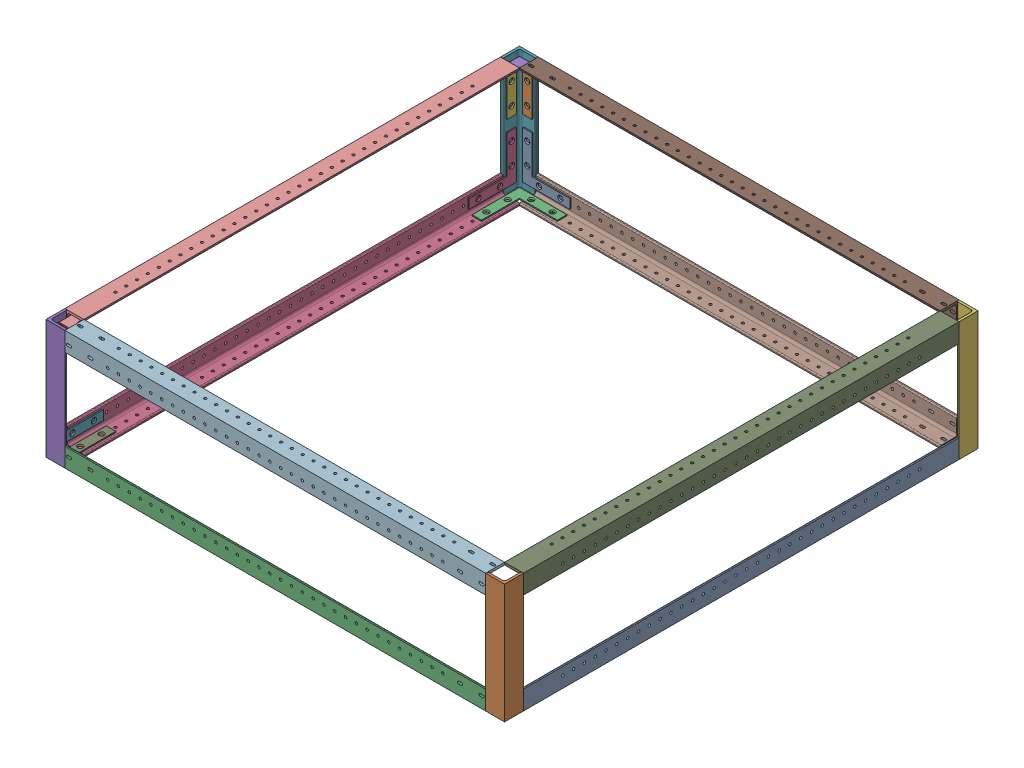
SolidWorks assembly Frame Assembly, configuration Default. Lengths in mm.
Overall size (614.8 160 634.8).
27 component instances, 4 part files, 110 mates.
Components (placement in the parent):
- 1 inch 584mm L Angle-1: 1 inch 584mm L Angle [8982K404] at (148.0756 139.9315 -175.8102) size (25.4 25.4 584)
- 1 inch 160mm L Angle-5: 1 inch 160mm L Angle [8982K404] at (148.0756 -322.3685 446.4898) x (1 0 0) z (0 1 0) size (25.4 25.4 160)
- 1 inch 564mm L Angle-3: 1 inch 564mm L Angle [8982K404] at (180.9756 139.9315 446.4898) x (0 0 1) z (-1 0 0) size (25.4 25.4 564)
- 1 inch 584mm L Angle-2: 1 inch 584mm L Angle [8982K404] at (-441.3244 139.9315 -175.8102) x (0 -1 0) z (0 0 1) size (25.4 25.4 584)
- 1 inch 160mm L Angle-2: 1 inch 160mm L Angle [8982K404] at (-441.3244 736.8315 446.4898) x (-1 0 0) z (0 -1 0) size (25.4 25.4 160)
- 1 inch 160mm L Angle-3: 1 inch 160mm L Angle [8982K404] at (148.0756 736.8315 -162.9102) x (1 0 0) z (0 -1 0) size (25.4 25.4 160)
- 1 inch 160mm L Angle-4: 1 inch 160mm L Angle [8982K404] at (-441.3244 736.8315 -162.9102) x (0 0 -1) z (0 -1 0) size (25.4 25.4 160)
- 1 inch 564mm L Angle-2: 1 inch 564mm L Angle [8982K404] at (-474.2244 139.9315 -162.9102) x (0 0 -1) z (1 0 0) size (25.4 25.4 564) (hidden)
- 1 inch 584mm L Angle-3: 1 inch 584mm L Angle [8982K404] at (148.0756 274.5315 -175.8102) x (0 1 0) z (0 0 1) size (25.4 25.4 584)
- 1 inch 584mm L Angle-4: 1 inch 584mm L Angle [8982K404] at (-441.3244 274.5315 -175.8102) x (-1 0 0) z (0 0 1) size (25.4 25.4 584)
- 1 inch 564mm L Angle-4: 1 inch 564mm L Angle [8982K404] at (-474.2244 274.5315 -162.9102) x (0 1 0) z (1 0 0) size (25.4 25.4 564) (hidden)
- 1 inch 564mm L Angle-5: 1 inch 564mm L Angle [8982K404] at (180.9756 274.5315 446.4898) x (0 1 0) z (-1 0 0) size (25.4 25.4 564) (hidden)
- 1558A14_L-Shape Flat-Surface Bracket with 2-1-2 Long Sides (2)-2: 1558A14_L-Shape Flat-Surface Bracket with 2-1-2 Long Sides (2) [1558A14] at (-413.5419 167.714 -171.6732) size (63.5 63.5 1.52)
- 1558A14_L-Shape Flat-Surface Bracket with 2-1-2 Long Sides (2)-3: 1558A14_L-Shape Flat-Surface Bracket with 2-1-2 Long Sides (2) [1558A14] at (-413.5419 246.749 -171.6732) x (0 -1 0) z (0 0 1) size (63.5 63.5 1.52)
- 1558A14_L-Shape Flat-Surface Bracket with 2-1-2 Long Sides (2)-4: 1558A14_L-Shape Flat-Surface Bracket with 2-1-2 Long Sides (2) [1558A14] at (-413.5419 131.1685 -135.1277) x (0 0 1) z (0 1 0) size (63.5 63.5 1.52)
- 1558A14_L-Shape Flat-Surface Bracket with 2-1-2 Long Sides (2)-6: 1558A14_L-Shape Flat-Surface Bracket with 2-1-2 Long Sides (2) [1558A14] at (-450.0874 167.714 -135.1302) x (0 1 0) z (1 0 0) size (63.5 63.5 1.52)
- 1558A14_L-Shape Flat-Surface Bracket with 2-1-2 Long Sides (2)-8: 1558A14_L-Shape Flat-Surface Bracket with 2-1-2 Long Sides (2) [1558A14] at (-413.5419 283.2945 -135.1277) x (1 0 0) z (0 -1 0) size (63.5 63.5 1.52)
- 1558A14_L-Shape Flat-Surface Bracket with 2-1-2 Long Sides (2)-27: 1558A14_L-Shape Flat-Surface Bracket with 2-1-2 Long Sides (2) [1558A14] at (-450.0874 246.7515 -135.1302) x (0 0 1) z (1 0 0) size (63.5 63.5 1.52)
- 1558A14_L-Shape Flat-Surface Bracket with 2-1-2 Long Sides (2)-36: 1558A14_L-Shape Flat-Surface Bracket with 2-1-2 Long Sides (2) [1558A14] at (-450.0874 167.714 418.7073) x (0 0 -1) z (1 0 0) size (63.5 63.5 1.52)
- 1558A14_L-Shape Flat-Surface Bracket with 2-1-2 Long Sides (2)-37: 1558A14_L-Shape Flat-Surface Bracket with 2-1-2 Long Sides (2) [1558A14] at (-413.5419 167.714 455.2528) x (0 1 0) z (0 0 -1) size (63.5 63.5 1.52)
- 1558A14_L-Shape Flat-Surface Bracket with 2-1-2 Long Sides (2)-38: 1558A14_L-Shape Flat-Surface Bracket with 2-1-2 Long Sides (2) [1558A14] at (-413.5419 131.1685 418.7073) x (1 0 0) z (0 1 0) size (63.5 63.5 1.52)
- 1558A14_L-Shape Flat-Surface Bracket with 2-1-2 Long Sides (2)-39: 1558A14_L-Shape Flat-Surface Bracket with 2-1-2 Long Sides (2) [1558A14] at (-413.5419 283.2945 418.7073) x (0 0 -1) z (0 -1 0) size (63.5 63.5 1.52)
- 1558A14_L-Shape Flat-Surface Bracket with 2-1-2 Long Sides (2)-40: 1558A14_L-Shape Flat-Surface Bracket with 2-1-2 Long Sides (2) [1558A14] at (-450.0874 246.749 418.7073) x (0 -1 0) z (1 0 0) size (63.5 63.5 1.52)
- 1558A14_L-Shape Flat-Surface Bracket with 2-1-2 Long Sides (2)-41: 1558A14_L-Shape Flat-Surface Bracket with 2-1-2 Long Sides (2) [1558A14] at (-413.5419 246.749 455.2528) x (1 0 0) z (0 0 -1) size (63.5 63.5 1.52)
- 1558A14_L-Shape Flat-Surface Bracket with 2-1-2 Long Sides (2)-42: 1558A14_L-Shape Flat-Surface Bracket with 2-1-2 Long Sides (2) [1558A14] at (120.2931 167.714 455.2528) x (-1 0 0) z (0 0 -1) size (63.5 63.5 1.52)
- 1558A14_L-Shape Flat-Surface Bracket with 2-1-2 Long Sides (2)-43: 1558A14_L-Shape Flat-Surface Bracket with 2-1-2 Long Sides (2) [1558A14] at (120.2931 131.1685 418.7073) x (0 0 -1) z (0 1 0) size (63.5 63.5 1.52)
- 1558A14_L-Shape Flat-Surface Bracket with 2-1-2 Long Sides (2)-44: 1558A14_L-Shape Flat-Surface Bracket with 2-1-2 Long Sides (2) [1558A14] at (156.8386 167.714 418.7073) x (0 1 0) z (-1 0 0) size (63.5 63.5 1.52)
Mates (geometry in assembly coordinates):
- Parallel1: parallel aligned: plane of 1 inch 584mm L Angle-1 through (159.1881 151.044 433.7898) normal (0 0 1); plane of 1 inch 160mm L Angle-5 through (135.3756 287.2315 459.1898) normal (0 0 1)
- Coincident3: coincident aligned: plane of 1 inch 584mm L Angle-1 through (160.7756 127.2315 433.7898) normal (1 0 0); plane of 1 inch 160mm L Angle-5 through (160.7756 287.2315 459.1898) normal (1 0 0)
- Coincident4: coincident anti-aligned: plane of 1 inch 584mm L Angle-1 through (159.1881 151.044 433.7898) normal (0 0 1); plane of 1 inch 160mm L Angle-5 through (159.1881 287.2315 433.7898) normal (0 0 -1)
- Parallel3: parallel aligned: plane of 1 inch 584mm L Angle-1 through (135.3756 127.2315 433.7898) normal (0 -1 0); plane of 1 inch 564mm L Angle-3 through (-428.6244 127.2315 433.7898) normal (0 -1 0)
- Coincident9: coincident aligned: plane of 1 inch 160mm L Angle-5 through (135.3756 287.2315 459.1898) normal (0 0 1); plane of 1 inch 564mm L Angle-3 through (-428.6244 127.2315 459.1898) normal (0 0 1)
- Parallel4: parallel anti-aligned: plane of 1 inch 564mm L Angle-3 through (-428.6244 130.4065 452.8398) normal (0 1 0); plane of 1 inch 584mm L Angle-2 through (-454.0244 127.2315 433.7898) normal (0 -1 0)
- Coincident12: coincident aligned: plane of 1 inch 564mm L Angle-3 through (-428.6244 127.2315 433.7898) normal (0 -1 0); plane of 1 inch 584mm L Angle-2 through (-454.0244 127.2315 433.7898) normal (0 -1 0)
- Coincident13: coincident anti-aligned: plane of 1 inch 564mm L Angle-3 through (-428.6244 151.044 457.6023) normal (-1 0 0); plane of 1 inch 584mm L Angle-2 through (-428.6244 128.819 433.7898) normal (1 0 0)
- Coincident15: coincident anti-aligned: plane of 1 inch 564mm L Angle-3 through (-428.6244 128.819 433.7898) normal (0 0 -1); plane of 1 inch 584mm L Angle-2 through (-430.2119 128.819 433.7898) normal (0 0 1)
- Coincident17: coincident aligned: plane of 1 inch 564mm L Angle-3 through (-428.6244 127.2315 459.1898) normal (0 0 1); plane of 1 inch 160mm L Angle-2 through (-428.6244 127.2315 459.1898) normal (0 0 1)
- Coincident18: coincident aligned: plane of 1 inch 584mm L Angle-2 through (-454.0244 152.6315 433.7898) normal (-1 0 0); plane of 1 inch 160mm L Angle-2 through (-454.0244 127.2315 459.1898) normal (-1 0 0)
- Coincident20: coincident aligned: plane of 1 inch 584mm L Angle-2 through (-454.0244 127.2315 433.7898) normal (0 -1 0); plane of 1 inch 160mm L Angle-2 through (-452.4369 127.2315 435.3773) normal (0 -1 0)
- Coincident21: coincident aligned: plane of 1 inch 584mm L Angle-1 through (135.3756 127.2315 433.7898) normal (0 -1 0); plane of 1 inch 160mm L Angle-3 through (159.1881 127.2315 -151.7977) normal (0 -1 0)
- Coincident22: coincident aligned: plane of 1 inch 584mm L Angle-1 through (160.7756 127.2315 433.7898) normal (1 0 0); plane of 1 inch 160mm L Angle-3 through (160.7756 127.2315 -175.6102) normal (1 0 0)
- Coincident25: coincident aligned: plane of 1 inch 584mm L Angle-2 through (-454.0244 127.2315 433.7898) normal (0 -1 0); plane of 1 inch 160mm L Angle-4 through (-430.2119 127.2315 -174.0227) normal (0 -1 0)
- Coincident26: coincident aligned: plane of 1 inch 584mm L Angle-2 through (-454.0244 152.6315 433.7898) normal (-1 0 0); plane of 1 inch 160mm L Angle-4 through (-454.0244 127.2315 -150.2102) normal (-1 0 0)
- Coincident28: coincident aligned: plane of 1 inch 160mm L Angle-3 through (135.3756 127.2315 -175.6102) normal (0 0 -1); plane of 1 inch 564mm L Angle-2 through (135.3756 127.2315 -175.6102) normal (0 0 -1)
- Coincident29: coincident aligned: plane of 1 inch 160mm L Angle-3 through (159.1881 127.2315 -151.7977) normal (0 -1 0); plane of 1 inch 564mm L Angle-2 through (135.3756 127.2315 -150.2102) normal (0 -1 0)
- Coincident30: coincident anti-aligned: plane of 1 inch 160mm L Angle-3 through (135.3756 127.2315 -174.0227) normal (-1 0 0); plane of 1 inch 564mm L Angle-2 through (135.3756 151.044 -174.0227) normal (1 0 0)
- Coincident31: coincident aligned: plane of 1 inch 160mm L Angle-5 through (159.1881 287.2315 435.3773) normal (0 1 0); plane of 1 inch 584mm L Angle-3 through (160.7756 287.2315 433.7898) normal (0 1 0)
- Coincident32: coincident aligned: plane of 1 inch 160mm L Angle-5 through (160.7756 287.2315 459.1898) normal (1 0 0); plane of 1 inch 584mm L Angle-3 through (160.7756 261.8315 433.7898) normal (1 0 0)
- Coincident33: coincident anti-aligned: plane of 1 inch 160mm L Angle-5 through (159.1881 287.2315 433.7898) normal (0 0 -1); plane of 1 inch 584mm L Angle-3 through (136.9631 285.644 433.7898) normal (0 0 1)
- Coincident35: coincident aligned: plane of 1 inch 160mm L Angle-4 through (-454.0244 127.2315 -150.2102) normal (-1 0 0); plane of 1 inch 584mm L Angle-4 through (-454.0244 287.2315 433.7898) normal (-1 0 0)
- Coincident37: coincident aligned: plane of 1 inch 584mm L Angle-3 through (160.7756 287.2315 433.7898) normal (0 1 0); plane of 1 inch 564mm L Angle-4 through (135.3756 287.2315 -175.6102) normal (0 1 0)
- Coincident38: coincident aligned: plane of 1 inch 160mm L Angle-3 through (135.3756 127.2315 -175.6102) normal (0 0 -1); plane of 1 inch 564mm L Angle-4 through (135.3756 261.8315 -175.6102) normal (0 0 -1)
- Coincident39: coincident anti-aligned: plane of 1 inch 160mm L Angle-3 through (135.3756 127.2315 -174.0227) normal (-1 0 0); plane of 1 inch 564mm L Angle-4 through (135.3756 285.644 -151.7977) normal (1 0 0)
- Coincident40: coincident aligned: plane of 1 inch 584mm L Angle-3 through (160.7756 287.2315 433.7898) normal (0 1 0); plane of 1 inch 564mm L Angle-5 through (-428.6244 287.2315 459.1898) normal (0 1 0)
- Coincident41: coincident aligned: plane of 1 inch 160mm L Angle-5 through (135.3756 287.2315 459.1898) normal (0 0 1); plane of 1 inch 564mm L Angle-5 through (-428.6244 261.8315 459.1898) normal (0 0 1)
- Coincident42: coincident anti-aligned: plane of 1 inch 160mm L Angle-2 through (-428.6244 127.2315 457.6023) normal (1 0 0); plane of 1 inch 564mm L Angle-5 through (-428.6244 285.644 435.3773) normal (-1 0 0)
- Coincident43: coincident anti-aligned: plane of 1 inch 160mm L Angle-4 through (-430.2119 127.2315 -172.4352) normal (0 0 1); plane of 1558A14_L-Shape Flat-Surface Bracket with 2-1-2 Long Sides (2)-1 through (-420.841 149.1963 -185.1352) normal (0 0 -1)
- Coincident53: coincident aligned: line of 160mm L Angle-4 through (-444.493 287.2315 -185.1352) axis (0 -1 0); line of 1558A16_L-Shape Flat-Surface Bracket with 3-1-2 Long Sides-1 through (-444.493 224.3159 -185.1352) axis (0 -1 0)
- Coincident54: coincident anti-aligned: plane of 1 inch 564mm L Angle-2 through (135.3756 151.044 -172.4352) normal (0 0 1); plane of 1558A16_L-Shape Flat-Surface Bracket with 3-1-2 Long Sides-1 through (-407.9805 179.8659 -178.7852) normal (0 0 -1)
- Coincident55: coincident anti-aligned: plane of 1 inch 584mm L Angle-2 through (-450.8494 133.5815 433.7898) normal (1 0 0); plane of 1558A16_L-Shape Flat-Surface Bracket with 3-1-2 Long Sides-2 through (-463.5494 179.2308 -129.5664) normal (-1 0 0)
- Coincident56: coincident anti-aligned: line of 160mm L Angle-4 through (-463.5494 287.2315 -166.0789) axis (0 -1 0); line of 1558A16_L-Shape Flat-Surface Bracket with 3-1-2 Long Sides-2 through (-463.5494 215.3195 -166.0789) axis (0 1 0)
- Coincident57: coincident anti-aligned: plane of 1 inch 584mm L Angle-2 through (-430.2119 130.4065 433.7898) normal (0 1 0); plane of 1558A16_L-Shape Flat-Surface Bracket with 3-1-2 Long Sides-3 through (-416.7224 130.4065 -132.7262) normal (0 -1 0)
- Parallel8: parallel anti-aligned: plane of 1 inch 584mm L Angle-2 through (-450.8494 133.5815 433.7898) normal (1 0 0); plane of 1558A16_L-Shape Flat-Surface Bracket with 3-1-2 Long Sides-3 through (-461.1724 132.3039 -88.2762) normal (-1 0 0)
- Coincident59: coincident aligned: plane of 1 inch 160mm L Angle-2 through (-423.5444 287.2315 433.7898) normal (0 1 0); plane of 1 inch 584mm L Angle-4 through (-428.6244 287.2315 433.7898) normal (0 1 0)
- Coincident60: coincident anti-aligned: plane of 1 inch 160mm L Angle-2 through (-452.4369 127.2315 433.7898) normal (0 0 -1); plane of 1 inch 584mm L Angle-4 through (-452.4369 263.419 433.7898) normal (0 0 1)
- Coincident61: coincident aligned: plane of 1 inch 160mm L Angle-2 through (-423.5444 287.2315 433.7898) normal (0 1 0); plane of 1 inch 564mm L Angle-5 through (-428.6244 287.2315 459.1898) normal (0 1 0)
- Coincident62: coincident aligned: plane of 1 inch 160mm L Angle-5 through (159.1881 287.2315 435.3773) normal (0 1 0); plane of 1 inch 564mm L Angle-5 through (-428.6244 287.2315 459.1898) normal (0 1 0)
- Coincident63: coincident anti-aligned: plane of 1 inch 160mm L Angle-5 through (135.3756 287.2315 457.6023) normal (-1 0 0); plane of 1 inch 564mm L Angle-5 through (135.3756 256.7515 433.7898) normal (1 0 0)
- Coincident64: coincident aligned: plane of 1 inch 160mm L Angle-4 through (-430.2119 127.2315 -174.0227) normal (0 -1 0); plane of 1 inch 564mm L Angle-2 through (135.3756 127.2315 -150.2102) normal (0 -1 0)
- Coincident65: coincident aligned: plane of 1 inch 584mm L Angle-2 through (-454.0244 152.6315 433.7898) normal (-1 0 0); plane of 1 inch 160mm L Angle-4 through (-454.0244 127.2315 -150.2102) normal (-1 0 0)
- Coincident66: coincident anti-aligned: plane of 1 inch 584mm L Angle-2 through (-428.6244 157.7115 -150.2102) normal (0 0 -1); plane of 1 inch 160mm L Angle-4 through (-452.4369 127.2315 -150.2102) normal (0 0 1)
- Coincident67: coincident aligned: plane of 1 inch 160mm L Angle-4 through (-454.0244 127.2315 -175.6102) normal (0 0 -1); plane of 1 inch 564mm L Angle-4 through (135.3756 261.8315 -175.6102) normal (0 0 -1)
- Coincident68: coincident anti-aligned: plane of 1 inch 160mm L Angle-4 through (-430.2119 127.2315 -172.4352) normal (0 0 1); plane of 1558A16_L-Shape Flat-Surface Bracket with 3-1-2 Long Sides-4 through (-401.6369 178.0315 -172.4352) normal (0 0 -1)
- Coincident69: coincident anti-aligned: plane of 1 inch 160mm L Angle-4 through (-450.8494 127.2315 -169.2602) normal (1 0 0); plane of 1558A16_L-Shape Flat-Surface Bracket with 3-1-2 Long Sides-5 through (-450.8494 178.0315 -123.2227) normal (-1 0 0)
- Coincident70: coincident: line of 1 inch 564mm L Angle-2 through (135.3756 133.5815 -172.4352) axis (-1 0 0); plane of 1558A16_L-Shape Flat-Surface Bracket with 3-1-2 Long Sides-4 through (-357.1869 133.5815 -170.5378) normal (0 -1 0)
- Coincident71: coincident: line of 1 inch 160mm L Angle-4 through (-430.2119 127.2315 -172.4352) axis (0 1 0); plane of 1558A16_L-Shape Flat-Surface Bracket with 3-1-2 Long Sides-4 through (-430.2119 222.4815 -170.5378) normal (1 0 0)
- Parallel9: parallel aligned: line of 1 inch 584mm L Angle-2 through (-450.8494 133.5815 433.7898) axis (0 0 -1); line of 1558A16_L-Shape Flat-Surface Bracket with 3-1-2 Long Sides-5 through (-448.952 133.5815 -78.7727) axis (0 0 -1)
- Coincident73: coincident: line of 1 inch 584mm L Angle-2 through (-450.8494 133.5815 433.7898) axis (0 0 -1); plane of 1558A16_L-Shape Flat-Surface Bracket with 3-1-2 Long Sides-5 through (-448.952 133.5815 -167.6727) normal (0 -1 0)
- Coincident74: coincident: line of 1 inch 160mm L Angle-4 through (-450.8494 127.2315 -151.7977) axis (0 1 0); plane of 1558A16_L-Shape Flat-Surface Bracket with 3-1-2 Long Sides-5 through (-448.952 149.4565 -151.7977) normal (0 0 1)
- Coincident75: coincident anti-aligned: plane of 1 inch 584mm L Angle-2 through (-430.2119 130.4065 433.7898) normal (0 1 0); plane of 1558A16_L-Shape Flat-Surface Bracket with 3-1-2 Long Sides-6 through (-401.6369 130.4065 -123.2227) normal (0 -1 0)
- Parallel10: parallel aligned: plane of 1 inch 584mm L Angle-2 through (-428.6244 128.819 433.7898) normal (1 0 0); plane of 1558A16_L-Shape Flat-Surface Bracket with 3-1-2 Long Sides-6 through (-430.2119 132.3039 -151.7977) normal (1 0 0)
- Coincident77: coincident: line of 1 inch 564mm L Angle-2 through (135.3756 130.4065 -151.7977) axis (-1 0 0); plane of 1558A16_L-Shape Flat-Surface Bracket with 3-1-2 Long Sides-6 through (-357.1869 132.3039 -151.7977) normal (0 0 1)
- Coincident78: coincident: line of 1 inch 584mm L Angle-2 through (-430.2119 130.4065 433.7898) axis (0 0 -1); plane of 1558A16_L-Shape Flat-Surface Bracket with 3-1-2 Long Sides-6 through (-430.2119 132.3039 -151.7977) normal (1 0 0)
- Coincident79: coincident anti-aligned: plane of 1 inch 584mm L Angle-2 through (-430.2119 130.4065 433.7898) normal (0 1 0); plane of 1558A16_L-Shape Flat-Surface Bracket with 3-1-2 Long Sides-7 through (-401.6369 130.4065 406.8023) normal (0 -1 0)
- Coincident80: coincident: line of 1 inch 564mm L Angle-3 through (-428.6244 130.4065 435.3773) axis (1 0 0); plane of 1558A16_L-Shape Flat-Surface Bracket with 3-1-2 Long Sides-7 through (-430.2119 132.3039 435.3773) normal (0 0 -1)
- Coincident81: coincident: line of 1 inch 584mm L Angle-2 through (-430.2119 130.4065 433.7898) axis (0 0 -1); plane of 1558A16_L-Shape Flat-Surface Bracket with 3-1-2 Long Sides-7 through (-430.2119 132.3039 362.3523) normal (1 0 0)
- Coincident82: coincident anti-aligned: plane of 1 inch 160mm L Angle-2 through (-450.8494 127.2315 435.3773) normal (1 0 0); plane of 1558A16_L-Shape Flat-Surface Bracket with 3-1-2 Long Sides-8 through (-450.8494 179.619 406.8023) normal (-1 0 0)
- Coincident83: coincident: line of 1 inch 160mm L Angle-2 through (-450.8494 127.2315 435.3773) axis (0 1 0); plane of 1558A16_L-Shape Flat-Surface Bracket with 3-1-2 Long Sides-8 through (-448.952 224.069 435.3773) normal (0 0 -1)
- Coincident84: coincident: line of 1 inch 584mm L Angle-2 through (-450.8494 151.044 433.7898) axis (0 0 -1); plane of 1558A16_L-Shape Flat-Surface Bracket with 3-1-2 Long Sides-8 through (-448.952 151.044 435.3773) normal (0 1 0)
- Coincident85: coincident: plane of 1 inch 160mm L Angle-4 through (-430.2119 127.2315 -172.4352) normal (0 0 1); plane of 1558A16_L-Shape Flat-Surface Bracket with 3-1-2 Long Sides-9 through (-389.7912 264.2838 -172.4352) normal (0 0 -1)
- Parallel11: parallel aligned: plane of 1 inch 160mm L Angle-4 through (-454.0244 127.2315 -150.2102) normal (-1 0 0); plane of 1558A16_L-Shape Flat-Surface Bracket with 3-1-2 Long Sides-9 through (-434.2412 219.8338 -170.5378) normal (-1 0 0)
- Coincident87: coincident anti-aligned: plane of 1 inch 160mm L Angle-4 through (-430.2119 127.2315 -172.4352) normal (0 0 1); plane of 1558A14_L-Shape Flat-Surface Bracket with 2-1-2 Long Sides (2)-2 through (-413.5419 167.714 -172.4352) normal (0 0 -1)
- Distance8: distance = 2.38 mm: line of 1 inch 564mm L Angle-2 through (135.3756 151.044 -172.4352) axis (-1 0 0); line of 1558A14_L-Shape Flat-Surface Bracket with 2-1-2 Long Sides (2)-2 through (-381.7919 148.664 -172.4352) axis (-1 0 0)
- Distance9: distance = 2.38 mm: line of 1 inch 160mm L Angle-4 through (-430.2119 127.2315 -172.4352) axis (0 1 0); plane of 1558A14_L-Shape Flat-Surface Bracket with 2-1-2 Long Sides (2)-2 through (-432.5919 199.464 -170.9112) normal (1 0 0)
- Coincident90: coincident anti-aligned: plane of 1 inch 160mm L Angle-4 through (-430.2119 127.2315 -172.4352) normal (0 0 1); plane of 1558A14_L-Shape Flat-Surface Bracket with 2-1-2 Long Sides (2)-3 through (-413.5419 246.749 -172.4352) normal (0 0 -1)
- Parallel12: parallel aligned: plane of 1 inch 160mm L Angle-4 through (-450.8494 127.2315 -169.2602) normal (1 0 0); plane of 1558A14_L-Shape Flat-Surface Bracket with 2-1-2 Long Sides (2)-3 through (-381.7919 278.499 -170.9112) normal (1 0 0)
- Distance14: distance = 2.38 mm: line of 1 inch 160mm L Angle-4 through (-430.2119 127.2315 -172.4352) axis (0 1 0); plane of 1558A14_L-Shape Flat-Surface Bracket with 2-1-2 Long Sides (2)-3 through (-432.5919 265.799 -170.9112) normal (1 0 0)
- Distance13: distance = 2.38 mm: line of 1 inch 564mm L Angle-4 through (135.3756 263.419 -172.4352) axis (-1 0 0); plane of 1558A14_L-Shape Flat-Surface Bracket with 2-1-2 Long Sides (2)-3 through (-381.7919 265.799 -170.9112) normal (0 -1 0)
- Coincident94: coincident anti-aligned: plane of 1 inch 564mm L Angle-2 through (135.3756 130.4065 -169.2602) normal (0 1 0); plane of 1558A14_L-Shape Flat-Surface Bracket with 2-1-2 Long Sides (2)-4 through (-413.5419 130.4065 -135.1277) normal (0 -1 0)
- Distance4: distance = 2.38 mm: line of 1 inch 564mm L Angle-2 through (135.3756 130.4065 -151.7977) axis (-1 0 0); line of 1558A14_L-Shape Flat-Surface Bracket with 2-1-2 Long Sides (2)-4 through (-432.5919 130.4065 -154.1777) axis (1 0 0)
- Coincident99: coincident anti-aligned: plane of 1 inch 160mm L Angle-4 through (-450.8494 127.2315 -169.2602) normal (1 0 0); plane of 1558A14_L-Shape Flat-Surface Bracket with 2-1-2 Long Sides (2)-6 through (-450.8494 167.714 -135.1302) normal (-1 0 0)
- Distance12: distance = 2.38 mm: line of 1 inch 160mm L Angle-4 through (-450.8494 127.2315 -169.2602) axis (0 1 0); plane of 1558A14_L-Shape Flat-Surface Bracket with 2-1-2 Long Sides (2)-6 through (-449.3254 199.464 -166.8802) normal (0 0 -1)
- Distance11: distance = 2.38 mm: line of 1 inch 584mm L Angle-2 through (-450.8494 151.044 433.7898) axis (0 0 -1); plane of 1558A14_L-Shape Flat-Surface Bracket with 2-1-2 Long Sides (2)-6 through (-449.3254 148.664 -103.3802) normal (0 1 0)
- Distance16: distance = 2.38 mm: line of 1 inch 584mm L Angle-4 through (-430.2119 284.0565 433.7898) axis (0 0 -1); plane of 1558A14_L-Shape Flat-Surface Bracket with 2-1-2 Long Sides (2)-8 through (-432.5919 282.5325 -103.3777) normal (1 0 0)
- Distance17: distance = 2.38 mm: line of 1 inch 564mm L Angle-4 through (135.3756 284.0565 -151.7977) axis (-1 0 0); plane of 1558A14_L-Shape Flat-Surface Bracket with 2-1-2 Long Sides (2)-8 through (-432.5919 282.5325 -154.1777) normal (0 0 1)
- Distance7: distance = 2.38 mm: plane of 1558A14_L-Shape Flat-Surface Bracket with 2-1-2 Long Sides (2)-4 through (-432.5919 131.9305 -154.1777) normal (1 0 0); line of 1 inch 584mm L Angle-2 through (-430.2119 130.4065 433.7898) axis (0 0 -1)
- Coincident121: coincident anti-aligned: plane of 1 inch 564mm L Angle-4 through (135.3756 284.0565 -151.7977) normal (0 -1 0); plane of 1558A14_L-Shape Flat-Surface Bracket with 2-1-2 Long Sides (2)-8 through (-413.5419 284.0565 -135.1277) normal (0 1 0)
- Coincident122: coincident anti-aligned: plane of 1 inch 160mm L Angle-4 through (-450.8494 127.2315 -169.2602) normal (1 0 0); plane of 1558A14_L-Shape Flat-Surface Bracket with 2-1-2 Long Sides (2)-27 through (-450.8494 246.7515 -135.1302) normal (-1 0 0)
- Distance18: distance = 2.38 mm: plane of 1558A14_L-Shape Flat-Surface Bracket with 2-1-2 Long Sides (2)-27 through (-449.3254 278.5015 -103.3802) normal (0 1 0); line of 1 inch 584mm L Angle-4 through (-450.8494 280.8815 433.7898) axis (0 0 -1)
- Distance19: distance = 2.38 mm: plane of 1558A14_L-Shape Flat-Surface Bracket with 2-1-2 Long Sides (2)-27 through (-449.3254 278.5015 -166.8802) normal (0 0 -1); line of 1 inch 160mm L Angle-4 through (-450.8494 127.2315 -169.2602) axis (0 1 0)
- Coincident126: coincident anti-aligned: plane of 1 inch 584mm L Angle-4 through (-450.8494 263.419 433.7898) normal (1 0 0); plane of 1558A14_L-Shape Flat-Surface Bracket with 2-1-2 Long Sides (2)-36 through (-450.8494 167.714 418.7073) normal (-1 0 0)
- Distance20: distance = 2.38 mm: plane of 1558A14_L-Shape Flat-Surface Bracket with 2-1-2 Long Sides (2)-36 through (-449.3254 148.664 437.7573) normal (0 1 0); line of 1 inch 584mm L Angle-2 through (-450.8494 151.044 433.7898) axis (0 0 -1)
- Distance21: distance = 2.38 mm: plane of 1558A14_L-Shape Flat-Surface Bracket with 2-1-2 Long Sides (2)-36 through (-449.3254 199.464 437.7573) normal (0 0 -1); line of 1 inch 160mm L Angle-2 through (-450.8494 127.2315 435.3773) axis (0 1 0)
- Coincident129: coincident anti-aligned: plane of 1 inch 564mm L Angle-3 through (-428.6244 151.044 456.0148) normal (0 0 -1); plane of 1558A14_L-Shape Flat-Surface Bracket with 2-1-2 Long Sides (2)-37 through (-413.5419 167.714 456.0148) normal (0 0 1)
- Distance22: distance = 2.38 mm: plane of 1558A14_L-Shape Flat-Surface Bracket with 2-1-2 Long Sides (2)-37 through (-381.7919 148.664 454.4908) normal (0 1 0); line of 1 inch 564mm L Angle-3 through (-428.6244 151.044 456.0148) axis (1 0 0)
- Distance23: distance = 2.38 mm: plane of 1558A14_L-Shape Flat-Surface Bracket with 2-1-2 Long Sides (2)-37 through (-432.5919 148.664 454.4908) normal (1 0 0); line of 1 inch 160mm L Angle-2 through (-430.2119 127.2315 456.0148) axis (0 1 0)
- Coincident132: coincident anti-aligned: plane of 1 inch 584mm L Angle-2 through (-430.2119 130.4065 433.7898) normal (0 1 0); plane of 1558A14_L-Shape Flat-Surface Bracket with 2-1-2 Long Sides (2)-38 through (-413.5419 130.4065 418.7073) normal (0 -1 0)
- Distance24: distance = 2.38 mm: plane of 1558A14_L-Shape Flat-Surface Bracket with 2-1-2 Long Sides (2)-38 through (-432.5919 131.9305 437.7573) normal (0 0 -1); line of 1 inch 564mm L Angle-3 through (-428.6244 130.4065 435.3773) axis (1 0 0)
- Distance25: distance = 2.38 mm: plane of 1558A14_L-Shape Flat-Surface Bracket with 2-1-2 Long Sides (2)-38 through (-432.5919 131.9305 386.9573) normal (1 0 0); line of 1 inch 584mm L Angle-2 through (-430.2119 130.4065 433.7898) axis (0 0 -1)
- Coincident135: coincident anti-aligned: plane of 1 inch 564mm L Angle-5 through (-428.6244 284.0565 435.3773) normal (0 -1 0); plane of 1558A14_L-Shape Flat-Surface Bracket with 2-1-2 Long Sides (2)-39 through (-413.5419 284.0565 418.7073) normal (0 1 0)
- Distance26: distance = 2.38 mm: plane of 1558A14_L-Shape Flat-Surface Bracket with 2-1-2 Long Sides (2)-39 through (-381.7919 282.5325 437.7573) normal (0 0 -1); line of 1 inch 564mm L Angle-5 through (-428.6244 284.0565 435.3773) axis (1 0 0)
- Distance27: distance = 2.38 mm: plane of 1558A14_L-Shape Flat-Surface Bracket with 2-1-2 Long Sides (2)-39 through (-432.5919 282.5325 437.7573) normal (1 0 0); line of 1 inch 584mm L Angle-4 through (-430.2119 284.0565 433.7898) axis (0 0 -1)
- Coincident138: coincident anti-aligned: plane of 1 inch 584mm L Angle-4 through (-450.8494 263.419 433.7898) normal (1 0 0); plane of 1558A14_L-Shape Flat-Surface Bracket with 2-1-2 Long Sides (2)-40 through (-450.8494 246.749 418.7073) normal (-1 0 0)
- Distance28: distance = 2.38 mm: plane of 1558A14_L-Shape Flat-Surface Bracket with 2-1-2 Long Sides (2)-40 through (-449.3254 265.799 386.9573) normal (0 -1 0); line of 1 inch 584mm L Angle-4 through (-450.8494 263.419 433.7898) axis (0 0 -1)
- Distance29: distance = 2.38 mm: plane of 1558A14_L-Shape Flat-Surface Bracket with 2-1-2 Long Sides (2)-40 through (-449.3254 265.799 437.7573) normal (0 0 -1); line of 1 inch 160mm L Angle-2 through (-450.8494 127.2315 435.3773) axis (0 1 0)
- Coincident141: coincident anti-aligned: plane of 1 inch 160mm L Angle-2 through (-447.6744 127.2315 456.0148) normal (0 0 -1); plane of 1558A14_L-Shape Flat-Surface Bracket with 2-1-2 Long Sides (2)-41 through (-413.5419 246.749 456.0148) normal (0 0 1)
- Distance30: distance = 2.38 mm: plane of 1558A14_L-Shape Flat-Surface Bracket with 2-1-2 Long Sides (2)-41 through (-432.5919 265.799 454.4908) normal (0 -1 0); line of 1 inch 564mm L Angle-5 through (-428.6244 263.419 456.0148) axis (1 0 0)
- Distance31: distance = 2.38 mm: plane of 1558A14_L-Shape Flat-Surface Bracket with 2-1-2 Long Sides (2)-41 through (-432.5919 214.999 454.4908) normal (1 0 0); line of 1 inch 160mm L Angle-2 through (-430.2119 127.2315 456.0148) axis (0 1 0)
- Coincident144: coincident anti-aligned: plane of 1 inch 564mm L Angle-3 through (-428.6244 151.044 456.0148) normal (0 0 -1); plane of 1558A14_L-Shape Flat-Surface Bracket with 2-1-2 Long Sides (2)-42 through (120.2931 167.714 456.0148) normal (0 0 1)
- Distance32: distance = 2.38 mm: plane of 1558A14_L-Shape Flat-Surface Bracket with 2-1-2 Long Sides (2)-42 through (139.3431 148.664 454.4908) normal (0 1 0); line of 1 inch 564mm L Angle-3 through (-428.6244 151.044 456.0148) axis (1 0 0)
- Distance33: distance = 2.38 mm: plane of 1558A14_L-Shape Flat-Surface Bracket with 2-1-2 Long Sides (2)-42 through (139.3431 199.464 454.4908) normal (-1 0 0); line of 1 inch 160mm L Angle-5 through (136.9631 287.2315 456.0148) axis (0 -1 0)
- Coincident147: coincident anti-aligned: plane of 1 inch 564mm L Angle-3 through (-428.6244 130.4065 452.8398) normal (0 1 0); plane of 1558A14_L-Shape Flat-Surface Bracket with 2-1-2 Long Sides (2)-43 through (120.2931 130.4065 418.7073) normal (0 -1 0)
- Distance34: distance = 2.38 mm: plane of 1558A14_L-Shape Flat-Surface Bracket with 2-1-2 Long Sides (2)-43 through (139.3431 131.9305 437.7573) normal (-1 0 0); line of 1 inch 584mm L Angle-1 through (136.9631 130.4065 433.7898) axis (0 0 -1)
- Distance35: distance = 2.38 mm: plane of 1558A14_L-Shape Flat-Surface Bracket with 2-1-2 Long Sides (2)-43 through (88.5431 131.9305 437.7573) normal (0 0 -1); line of 1 inch 564mm L Angle-3 through (-428.6244 130.4065 435.3773) axis (1 0 0)
- Coincident150: coincident anti-aligned: plane of 1 inch 160mm L Angle-5 through (157.6006 287.2315 435.3773) normal (-1 0 0); plane of 1558A14_L-Shape Flat-Surface Bracket with 2-1-2 Long Sides (2)-44 through (157.6006 167.714 418.7073) normal (1 0 0)
- Distance36: distance = 2.38 mm: plane of 1558A14_L-Shape Flat-Surface Bracket with 2-1-2 Long Sides (2)-44 through (156.0766 148.664 386.9573) normal (0 1 0); line of 1 inch 584mm L Angle-1 through (157.6006 151.044 433.7898) axis (0 0 -1)
- Distance37: distance = 2.38 mm: plane of 1558A14_L-Shape Flat-Surface Bracket with 2-1-2 Long Sides (2)-44 through (156.0766 148.664 437.7573) normal (0 0 -1); line of 1 inch 160mm L Angle-5 through (157.6006 287.2315 435.3773) axis (0 -1 0)
